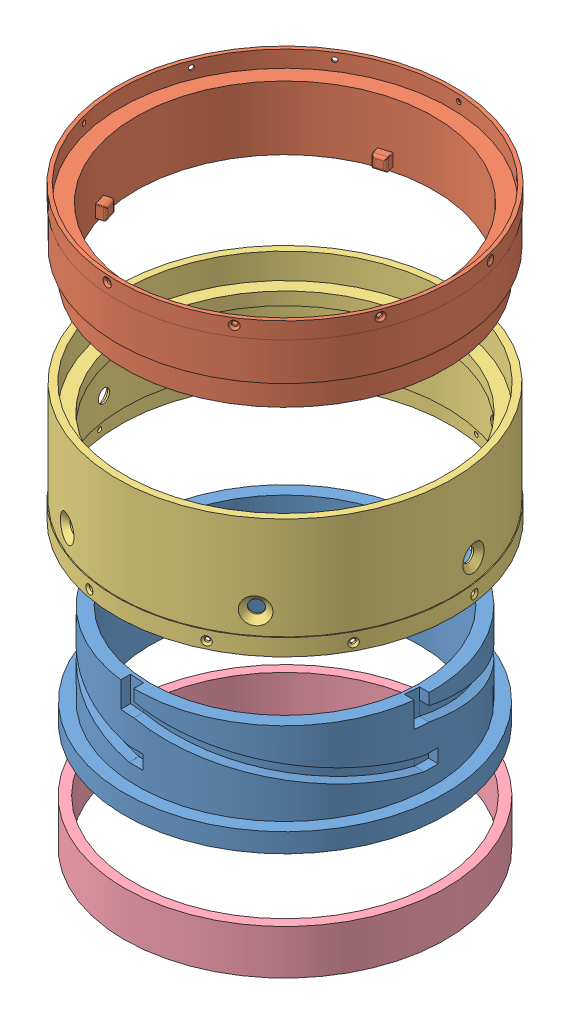
SolidWorks assembly proto_assemb, configuration Default. Lengths in mm.
Overall size (208.72 286.09 208.72).
4 component instances, 4 part files, 3 mates.
Components (placement in the parent):
- twist_coupling-1: twist_coupling [Default] at (-111.3098 -13.4473 60.3229) size (159.51 50.8 159.51)
- Bottom_ring-1: Bottom_ring [Default] at (-111.3098 162.5616 60.3229) x (0.287147 0 0.957887) z (-0.957887 0 0.287147) size (167.64 40.01 167.64)
- Top_ring-1: Top_ring [Default] at (-111.3098 108.6769 60.3229) x (-0.988778 0 -0.149394) z (0.149394 0 -0.988778) size (167.64 59.18 167.64)
- kepper ring-1: kepper ring [Default] at (-111.3098 -81.202 60.3229) x (0.998196 0 0.060041) z (-0.060041 0 0.998196) size (159.77 22.23 159.77)
Mates (geometry in assembly coordinates):
- Concentric1: concentric aligned: cylinder of Bottom_ring-1 through (-111.3098 211.7051 60.3229) axis (0 1 0) radius 79.9338; cylinder of Top_ring-1 through (-111.3098 108.6769 60.3229) axis (0 1 0) radius 79.9922
- Concentric2: concentric aligned: cylinder of twist_coupling-1 through (-111.3098 47.3107 60.3229) axis (0 1 0) radius 73.533; cylinder of Top_ring-1 through (-111.3098 108.6769 60.3229) axis (0 1 0) radius 73.6422
- Concentric3: concentric anti-aligned: cylinder of Top_ring-1 through (-111.3098 108.6769 60.3229) axis (0 1 0) radius 79.9922; cylinder of kepper ring-1 through (-111.3098 -58.977 60.3229) axis (0 -1 0) radius 79.883
